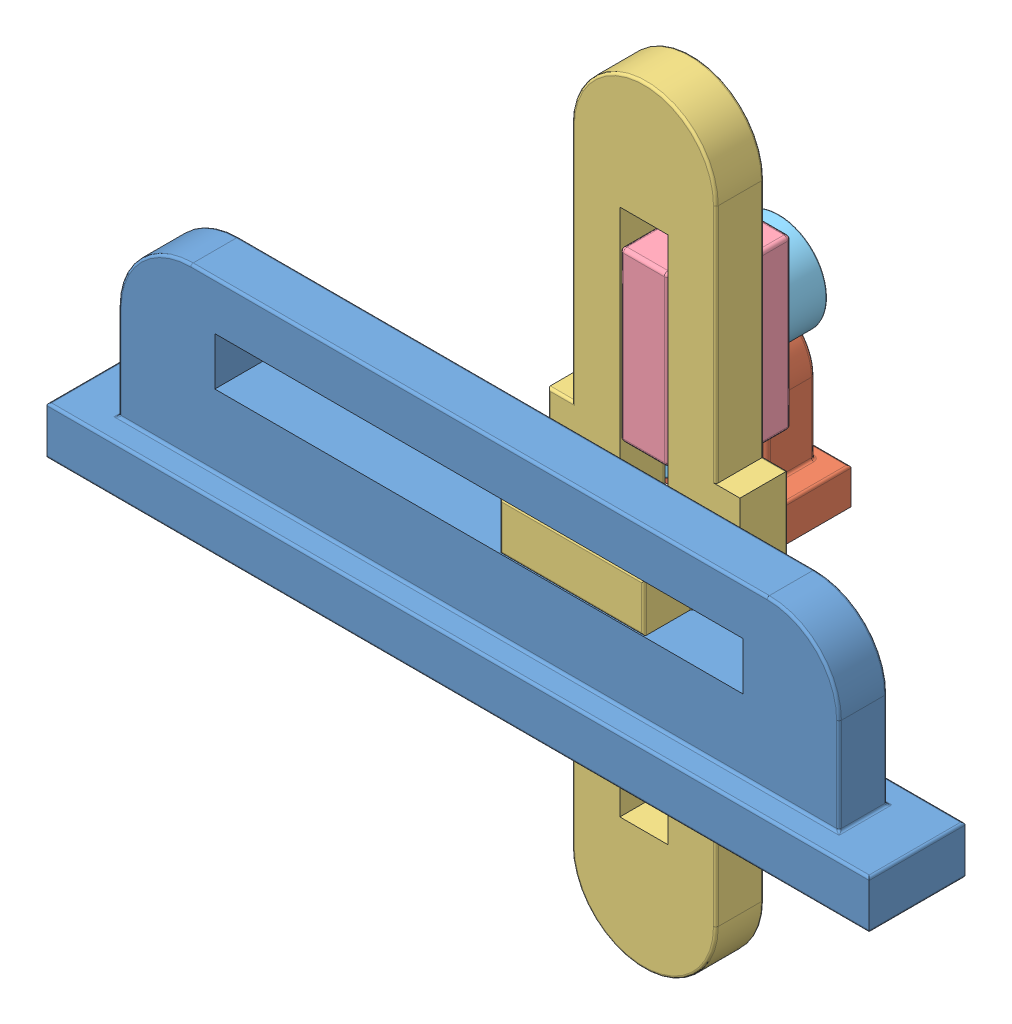
SolidWorks assembly SliderCrank, configuration Default. Lengths in mm.
Overall size (342.57 320 135).
6 component instances, 6 part files, 14 mates.
Components (placement in the parent):
- Slider Body-2: Slider Body [Default] at (60 35 -10) x (1 0 0) z (0 -1 0) size (342.57 40 90)
- Rotor-2: Rotor [Default] at (140 15 -85) x (1 0 0) z (0 -1 0) size (60 30 65)
- Slider-1: Slider [Default] at (208.7204 175 -40) size (80 320 50)
- Connector-1: Connector [Default] at (230.0538 105.5907 -60) x (-1 0 0) z (0 0 -1) size (50 70 60)
- Connecting-rod-1: Connecting-rod [Default] at (205.0538 105.5907 -70) x (0.865582 -0.500768 0) z (0 0 1) size (40 110 20)
- Connecting-Pin-1: Connecting-Pin [Default] at (170 45 -110) x (-0.740061 -0.67254 0) z (-0.67254 0.740061 0) size (20 50 20)
Mates (geometry in assembly coordinates):
- Coincident2: coincident anti-aligned: plane of Slider Body-2 through (60 35 0) normal (0 0 -1); plane of assembly through (0 0 0) normal (0 0 1)
- Coincident3: coincident aligned: plane of Slider Body-2 through (60 0 -10) normal (0 1 0); plane of assembly through (0 0 0) normal (0 1 0)
- Coincident4: coincident anti-aligned: plane of Slider Body-2 through (0 -15 20) normal (-1 0 0); plane of assembly through (0 0 0) normal (1 0 0)
- Coincident15: coincident anti-aligned: plane of Rotor-2 through (140 0 -85) normal (0 -1 0); plane of assembly through (0 0 0) normal (0 1 0)
- Coincident16: coincident: line of Slider Body-2; axis of Rotor-2 through (170 45 -91.5) axis (0 0 -1)
- Coincident17: coincident aligned: plane of Slider Body-2 through (50 45 10) normal (0 0 1); plane of Slider-1 through (208.7204 175 10) normal (0 0 1)
- Coincident18: coincident anti-aligned: plane of Slider Body-2 through (60 55 10) normal (0 -1 0); plane of Slider-1 through (178.7204 55 10) normal (0 1 0)
- Coincident19: coincident aligned: plane of Slider-1 through (208.7204 175 -20) normal (0 0 1); plane of Connector-1 through (218.7204 140.5907 -20) normal (0 0 1)
- Coincident20: coincident anti-aligned: plane of Slider-1 through (198.7204 -65 -20) normal (1 0 0); plane of Connector-1 through (198.7204 140.5907 -20) normal (-1 0 0)
- Coincident21: coincident aligned: plane of Connector-1 through (205.0538 105.5907 -80) normal (0 0 -1); plane of Connecting-rod-1 through (205.0538 105.5907 -80) normal (0 0 -1)
- Concentric1: concentric anti-aligned: cylinder of Connector-1 through (205.0538 105.5907 -80) axis (0 0 1) radius 10; cylinder of Connecting-rod-1 through (205.0538 105.5907 -60) axis (0 0 -1) radius 10
- Coincident22: coincident aligned: plane of Connecting-rod-1 through (205.0538 105.5907 -60) normal (0 0 1); plane of Connecting-Pin-1 through (170 45 -60) normal (0 0 1)
- Concentric2: concentric aligned: cylinder of Connecting-rod-1 through (170 45 -60) axis (0 0 -1) radius 10; cylinder of Connecting-Pin-1 through (170 45 -60) axis (0 0 -1) radius 10
- Concentric3: concentric aligned: cylinder of Rotor-2 through (170 45 -90) axis (0 0 -1) radius 10; cylinder of Connecting-Pin-1 through (170 45 -60) axis (0 0 -1) radius 10
